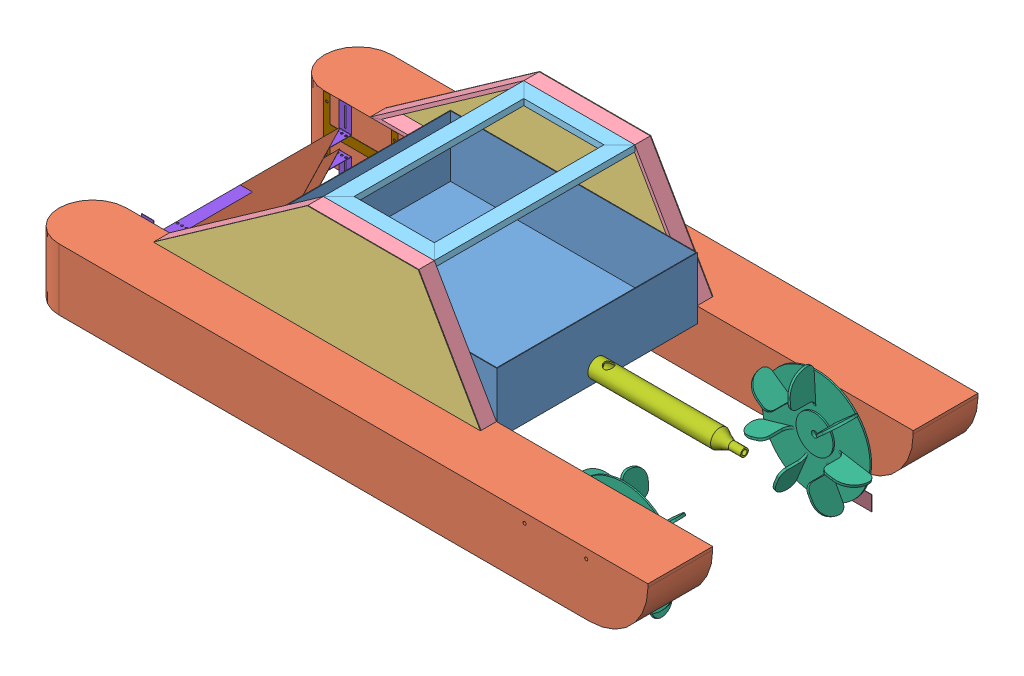
SolidWorks assembly Assem1, configuration Default. Lengths in mm.
Overall size (2010 856.74 1071).
23 component instances, 14 part files, 45 mates.
Components (placement in the parent):
- first tank-1: first tank [Default] at (-200.6218 404.7548 932.1456) size (800 200 650)
- Part1-1: Part1 [Default] at (-710.6218 254.7548 1142.1456) x (0 0 -1) z (1 0 0) size (210 200 2010)
- side-1: side [Default] at (-461.7175 454.7548 982.1456) size (1060 351.39 2)
- side metal structure-1: side metal structure [Default] at (-461.7175 454.7548 982.1456) size (1060 351.39 50)
- side-2: side [Default] at (-461.7175 454.7548 230.1456) size (1060 351.39 2)
- side metal structure-2: side metal structure [Default] at (-461.7175 454.7548 282.1456) size (1060 351.39 50)
- upper frame-1: upper frame [Default] at (396.9075 786.1422 932.1456) x (0 0 -1) z (1 0 0) size (650 20 360)
- Part1-4: Part1 [Default] at (-710.6218 254.7548 282.1456) x (0 0 -1) z (1 0 0) size (210 200 2010)
- fan-1: fan [Default] at (999.3782 304.7548 922.1456) x (0.924018 -0.382349 0) z (0.382349 0.924018 0) size (381.85 85 372.28)
- fan-2: fan [Default] at (999.3782 304.7548 292.1456) x (-0.924018 0.382349 0) z (0.382349 0.924018 0) size (381.85 85 372.28)
- water collector-1: water collector [Default] at (-553.1462 352.1521 607.1456) x (0 0 -1) z (1 0 0) size (617.38 161.13 335.01) (hidden)
- water lackaging-1: water lackaging [Default] at (597.3782 444.7548 607.1456) x (0 0.114459 -0.993428) z (1 0 0) size (60.28 60.21 480)
- fixing the fixing of water slot slider-1: fixing the fixing of water slot slider [Default] at (-600.6218 254.7548 931.1456) size (240 200 1) (hidden)
- fixing water slot-1: fixing water slot [Default] at (-513.1462 383.1521 291.1456) x (0 0 1) z (-1 0 0) size (642 81 40)
- fixing water slot-4: fixing water slot [Default] at (-359.6218 378.1521 290.1456) x (0 0 1) z (-1 0 0) size (642 81 40) (hidden)
- fixing the fixing of water slot slider-2: fixing the fixing of water slot slider [Default] at (-610.6218 254.7548 282.1456) size (240 200 1)
- fixing water slot-5: fixing water slot [Default] at (-553.1462 321.1521 291.1456) x (0 0 1) z (1 0 0) size (642 81 40)
- fixing water slot-6: fixing water slot [Default] at (-399.6218 326.1521 290.1456) x (0 0 1) z (1 0 0) size (642 81 40) (hidden)
- Bilge Pump-1: Bilge Pump [Default] at (-243.1462 366.1521 607.1456) x (0.725322 0 0.68841) z (-0.68841 0 0.725322) size (71.75 108.1 86.38)
- water collector2-1: water collector2 [Default] at (-553.1462 382.1521 286.1272) x (0 0 1) z (-1 0 0) size (640 1 150)
- water collector2-2: water collector2 [Default] at (-553.1462 322.1521 288.3038) x (0 0 1) z (-1 0 0) size (640 1 150)
- sides of water collector-2: sides of water collector [Default] at (-403.1462 383.1521 636.1272) x (0.888218 0 0.459423) z (0.459423 0 -0.888218) size (1 60 326)
- fixing the whole machine-1: fixing the whole machine [Default] at (884.3782 439.7548 71.1456) size (110.71 490.36 1)
Mates (geometry in assembly coordinates):
- Coincident1: coincident anti-aligned: plane of first tank-1 through (-200.6218 604.7548 932.1456) normal (0 0 1); plane of Part1-1 through (1299.3782 454.7548 932.1456) normal (0 0 -1)
- Distance1: distance = 700 mm aligned: plane of first tank-1 through (599.3782 604.7548 932.1456) normal (1 0 0); plane of Part1-1 through (1299.3782 454.7548 1142.1456) normal (1 0 0)
- Distance3: distance = 150 mm aligned: plane of first tank-1 through (-200.6218 404.7548 932.1456) normal (0 -1 0); plane of Part1-1 through (-710.6218 254.7548 1142.1456) normal (0 -1 0)
- Coincident4: coincident aligned: plane of Part1-1 through (1299.3782 454.7548 932.1456) normal (0 0 -1); plane of side metal structure-1 through (598.2825 454.7548 932.1456) normal (0 0 -1)
- Coincident5: coincident anti-aligned: plane of Part1-1 through (-710.6218 454.7548 1142.1456) normal (0 1 0); plane of side-1 through (-461.7175 454.7548 984.1456) normal (0 -1 0)
- Coincident6: coincident anti-aligned: plane of side-1 through (-461.7175 454.7548 982.1456) normal (0 0 -1); plane of side metal structure-1 through (598.2825 454.7548 982.1456) normal (0 0 1)
- Coincident7: coincident aligned: plane of side-1 through (396.9075 806.1422 984.1456) normal (0 1 0); plane of side metal structure-1 through (22.8411 806.1422 982.1456) normal (0 1 0)
- Coincident8: coincident: line of side-1 through (598.2825 454.7548 984.1456) axis (-0.497222 0.867623 0); plane of side metal structure-1 through (391.5676 815.4599 982.1456) normal (0.867623 0.497222 0)
- Coincident9: coincident anti-aligned: plane of side metal structure-2 through (22.8411 806.1422 282.1456) normal (0 0 1); plane of upper frame-1 through (396.9075 786.1422 282.1456) normal (0 0 -1)
- Coincident10: coincident aligned: plane of side metal structure-2 through (22.8411 806.1422 282.1456) normal (0 1 0); plane of upper frame-1 through (396.9075 806.1422 282.1456) normal (0 1 0)
- Coincident13: coincident: line of side metal structure-2 through (396.9075 806.1422 232.1456) axis (0 0 1); plane of upper frame-1 through (396.9075 786.1422 932.1456) normal (1 0 0)
- Concentric1: concentric anti-aligned: cylinder of Part1-1 through (999.3782 304.7548 942.1456) axis (0 0 -1) radius 10; cylinder of fan-1 through (999.3782 304.7548 922.1456) axis (0 0 1) radius 10
- Distance2: distance = 20 mm aligned: plane of Part1-1 through (1299.3782 454.7548 932.1456) normal (0 0 -1); plane of fan-1 through (999.3782 304.7548 912.1456) normal (0 0 -1)
- Distance4: distance = 352.5245 mm aligned: plane of water collector-1 through (-553.1462 372.1521 897.1456) normal (-1 0 0); plane of first tank-1 through (-200.6218 604.7548 932.1456) normal (-1 0 0)
- Distance6: distance = 25 mm: plane of first tank-1 through (-200.6218 604.7548 932.1456) normal (0 0 1); line of water collector-1 through (-553.1462 352.1521 907.1456) axis (0 -1 0)
- Coincident14: coincident aligned: plane of first tank-1 through (597.3782 406.7548 930.1456) normal (-1 0 0); plane of water lackaging-1 through (597.3782 444.7548 607.1456) normal (-1 0 0)
- Coincident15: coincident anti-aligned: circle of first tank-1; cylinder of water lackaging-1 through (997.3782 444.7548 607.1456) axis (-1 0 0) radius 30
- Coincident16: coincident anti-aligned: plane of Part1-1 through (1299.3782 454.7548 932.1456) normal (0 0 -1); plane of fixing the fixing of water slot slider-1 through (-600.6218 254.7548 932.1456) normal (0 0 1)
- Coincident17: coincident aligned: plane of Part1-1 through (-710.6218 454.7548 1142.1456) normal (0 1 0); plane of fixing the fixing of water slot slider-1 through (-600.6218 454.7548 932.1456) normal (0 1 0)
- Coincident18: coincident: line of Part1-1 through (-600.6218 254.7548 932.1456) axis (0 1 0); plane of fixing the fixing of water slot slider-1 through (-600.6218 254.7548 932.1456) normal (-1 0 0)
- Coincident19: coincident anti-aligned: plane of Part1-4 through (-710.6218 454.7548 282.1456) normal (0 0 1); plane of fixing the fixing of water slot slider-2 through (-610.6218 254.7548 282.1456) normal (0 0 -1)
- Coincident20: coincident aligned: plane of Part1-4 through (-710.6218 454.7548 282.1456) normal (0 1 0); plane of fixing the fixing of water slot slider-2 through (-610.6218 454.7548 283.1456) normal (0 1 0)
- Coincident21: coincident: line of Part1-4 through (-610.6218 454.7548 282.1456) axis (0 -1 0); plane of fixing the fixing of water slot slider-2 through (-610.6218 254.7548 283.1456) normal (-1 0 0)
- Parallel1: parallel anti-aligned: plane of fixing water slot-4 through (-399.6218 458.1521 289.1456) normal (0 0 -1); plane of fixing the fixing of water slot slider-2 through (-610.6218 254.7548 283.1456) normal (0 0 1)
- Tangent1: tangent anti-aligned: plane of fixing water slot-4 through (-376.6218 448.1521 289.1456) normal (-1 0 0); cylinder of fixing the fixing of water slot slider-2 through (-380.6218 429.7548 283.1456) axis (0 0 -1) radius 4
- Parallel2: parallel aligned: plane of Part1-4 through (-710.6218 454.7548 282.1456) normal (0 1 0); plane of fixing water slot-4 through (-399.6218 378.1521 290.1456) normal (0 1 0)
- Coincident24: coincident anti-aligned: plane of fixing the fixing of water slot slider-1 through (-600.6218 254.7548 931.1456) normal (0 0 -1); plane of fixing water slot-4 through (-399.6218 378.1521 931.1456) normal (0 0 1)
- Tangent2: tangent anti-aligned: cylinder of water collector-1 through (-393.1462 352.1521 607.1456) axis (1 0 0) radius 25; plane of fixing water slot-4 through (-399.6218 377.1521 290.1456) normal (0 -1 0)
- Coincident25: coincident aligned: plane of water collector-1 through (-553.1462 372.1521 897.1456) normal (-1 0 0); plane of fixing water slot-1 through (-553.1462 384.1521 290.1456) normal (-1 0 0)
- Coincident26: coincident anti-aligned: plane of Part1-1 through (1299.3782 454.7548 932.1456) normal (0 0 -1); plane of fixing water slot-1 through (-553.1462 383.1521 932.1456) normal (0 0 1)
- Coincident27: coincident: line of water collector-1 through (-553.1462 382.1521 897.1456) axis (0 0 -1); plane of fixing water slot-1 through (-553.1462 382.1521 291.1456) normal (0 -1 0)
- Concentric2: concentric anti-aligned: cylinder of water collector-1 through (-243.1462 292.1521 607.1456) axis (0 1 0) radius 25; cylinder of Bilge Pump-1 through (-243.1462 420.1521 607.1456) axis (0 -1 0) radius 28.875
- Coincident28: coincident anti-aligned: plane of water collector-1 through (-553.1462 312.1521 607.1456) normal (0 1 0); plane of Bilge Pump-1 through (-243.1462 312.1521 607.1456) normal (0 -1 0)
- Coincident37: coincident anti-aligned: plane of water collector2-1 through (-553.1462 383.1521 926.1272) normal (0.888218 0 0.459423); plane of sides of water collector-2 through (-403.1462 383.1521 636.1272) normal (-0.888218 0 -0.459423)
- Coincident39: coincident aligned: plane of water collector2-1 through (-553.1462 383.1521 286.1272) normal (0 1 0); plane of sides of water collector-2 through (-402.258 383.1521 636.5866) normal (0 1 0)
- Coincident41: coincident aligned: plane of water collector2-1 through (-553.1462 383.1521 286.1272) normal (-1 0 0); plane of water collector2-2 through (-553.1462 323.1521 288.3038) normal (-1 0 0)
- Coincident47: coincident anti-aligned: plane of fixing water slot-5 through (-513.1462 322.1521 291.1456) normal (0 1 0); plane of water collector2-2 through (-553.1462 322.1521 288.3038) normal (0 -1 0)
- Coincident48: coincident: point of water collector2-1; line of sides of water collector-2 through (-403.1462 383.1521 636.1272) axis (0 -1 0)
- Coincident49: coincident anti-aligned: plane of water collector2-2 through (-553.1462 323.1521 288.3038) normal (0 1 0); plane of sides of water collector-2 through (-402.258 323.1521 636.5866) normal (0 -1 0)
- Coincident50: coincident aligned: plane of water collector2-2 through (-553.1462 323.1521 928.3038) normal (0.888218 0 0.459423); plane of sides of water collector-2 through (-402.258 383.1521 636.5866) normal (0.888218 0 0.459423)
- Coincident51: coincident anti-aligned: plane of fixing water slot-5 through (-513.1462 322.1521 291.1456) normal (0 1 0); plane of water collector2-2 through (-553.1462 322.1521 288.3038) normal (0 -1 0)
- Coincident52: coincident aligned: plane of fixing water slot-5 through (-553.1462 320.1521 932.1456) normal (-1 0 0); plane of water collector2-2 through (-553.1462 323.1521 288.3038) normal (-1 0 0)
- Distance7: distance = 5 mm: plane of fixing the fixing of water slot slider-1 through (-600.6218 254.7548 931.1456) normal (0 0 -1); line of sides of water collector-2 through (-552.0299 323.1521 926.1456) axis (0 1 0)
- Coincident53: coincident anti-aligned: plane of Part1-4 through (1299.3782 454.7548 72.1456) normal (0 0 -1); plane of fixing the whole machine-1 through (884.3782 439.7548 72.1456) normal (0 0 1)
- Concentric3: concentric anti-aligned: cylinder of Part1-4 through (899.3782 424.7548 282.1456) axis (0 0 -1) radius 5; cylinder of fixing the whole machine-1 through (899.3782 424.7548 72.1456) axis (0 0 1) radius 5
